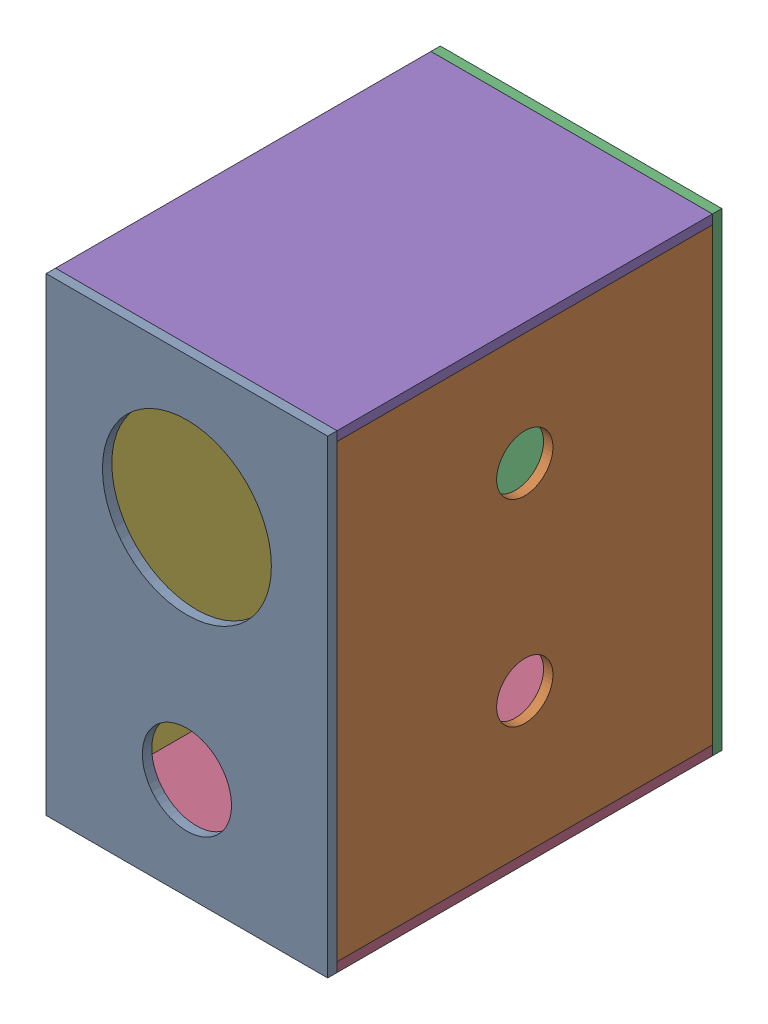
SolidWorks assembly Mirrorspeaker_full, configuration Default. Lengths in mm.
Overall size (300 500 420).
6 component instances, 5 part files, 13 mates.
Components (placement in the parent):
- Mirrorspeaker_front-1: Mirrorspeaker_front [Default] at (0 -1100.097 0) size (300 500 10)
- Mirrorspeaker_int_side-1: Mirrorspeaker_int_side [Default] at (300 -1110.097 -410) x (0 0 1) z (-1 0 0) size (400 480 10)
- Mirrorspeaker_rear-1: Mirrorspeaker_rear [Default] at (0 -1100.097 -420) size (300 500 10)
- Mirrorspeaker_top_bot-1: Mirrorspeaker_top_bot [Default] at (0 -500 690.097) x (1 0 0) z (0 1 0) size (300 400 10)
- Mirrorspeaker_top_bot-2: Mirrorspeaker_top_bot [Default] at (0 -10 690.097) x (1 0 0) z (0 1 0) size (300 400 10)
- Mirrorspeaker_ext_side-1: Mirrorspeaker_ext_side [Default] at (10 -1555.6347 -350.3682) x (0 0 1) z (-1 0 0) size (400 480 10)
Mates (geometry in assembly coordinates):
- Coincident1: coincident aligned: line of Mirrorspeaker_front-1; line of Mirrorspeaker_int_side-1
- Coincident2: coincident anti-aligned: plane of Mirrorspeaker_front-1 through (0 -500 -10) normal (0 0 -1); plane of Mirrorspeaker_int_side-1 through (290 -10 -10) normal (0 0 1)
- Coincident3: coincident anti-aligned: line of Mirrorspeaker_int_side-1; line of Mirrorspeaker_rear-1
- Coincident4: coincident aligned: plane of Mirrorspeaker_front-1 through (0 -500 -10) normal (0 -1 0); plane of Mirrorspeaker_rear-1 through (0 -500 -410) normal (0 -1 0)
- Coincident5: coincident anti-aligned: line of Mirrorspeaker_int_side-1; line of Mirrorspeaker_top_bot-1
- Coincident6: coincident aligned: plane of Mirrorspeaker_rear-1 through (0 -500 -410) normal (0 -1 0); plane of Mirrorspeaker_top_bot-1 through (0 -500 -10) normal (0 -1 0)
- Coincident7: coincident: plane of Mirrorspeaker_rear-1 through (0 -500 -410) normal (0 0 1); line of Mirrorspeaker_top_bot-1
- Coincident8: coincident anti-aligned: plane of Mirrorspeaker_rear-1 through (0 -500 -410) normal (0 0 1); plane of Mirrorspeaker_top_bot-2 through (0 0 -410) normal (0 0 -1)
- Coincident9: coincident aligned: plane of Mirrorspeaker_rear-1 through (0 0 -410) normal (0 1 0); plane of Mirrorspeaker_top_bot-2 through (0 0 -10) normal (0 1 0)
- Coincident10: coincident aligned: plane of Mirrorspeaker_int_side-1 through (300 -490 -410) normal (1 0 0); plane of Mirrorspeaker_top_bot-2 through (300 0 -410) normal (1 0 0)
- Coincident11: coincident aligned: line of Mirrorspeaker_rear-1; line of Mirrorspeaker_ext_side-1
- Coincident12: coincident anti-aligned: line of Mirrorspeaker_front-1; line of Mirrorspeaker_ext_side-1
- Coincident13: coincident: plane of Mirrorspeaker_top_bot-1 through (0 -490 -10) normal (0 1 0); line of Mirrorspeaker_ext_side-1
